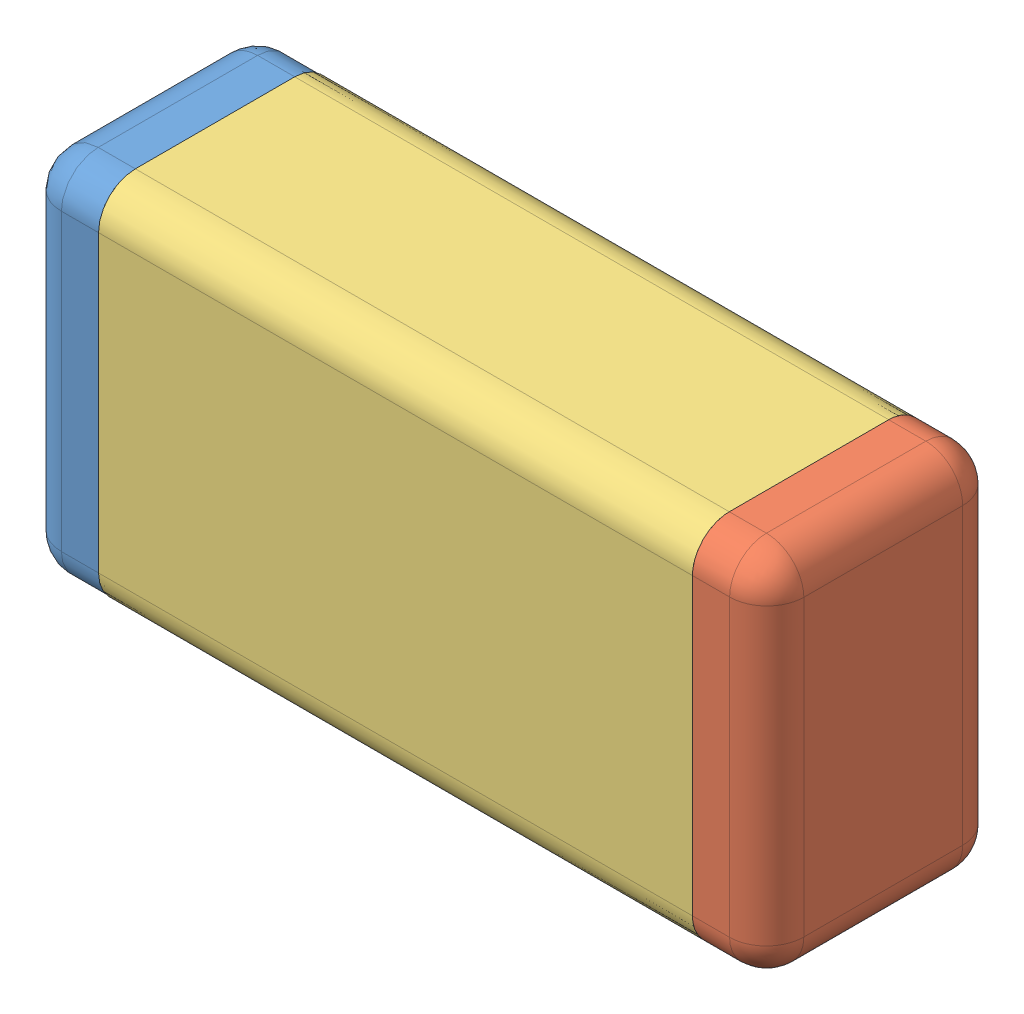
SolidWorks assembly C3_ASM, configuration Default. Lengths in mm.
Overall size (2.51 1.25 0.79).
4 component instances, 3 part files, 0 mates.
Components (placement in the parent):
- USER_LIBRARY-0805_2012M__CAP__1_ASM-1: USER_LIBRARY-0805_2012M__CAP__1_ASM [Default] at (16.2561 61.6965 -1.7324) x (1 0 0) z (0 1 0) size (2.51 0.79 1.25)
  - MANIFOLD_SOLID_BREP_12297-1: MANIFOLD_SOLID_BREP_12297 [Default] at origin size (0.25 0.79 1.25)
  - MANIFOLD_SOLID_BREP_13179-1: MANIFOLD_SOLID_BREP_13179 [Default] at origin size (0.25 0.79 1.25)
  - MANIFOLD_SOLID_BREP_13933-1: MANIFOLD_SOLID_BREP_13933 [Default] at origin size (2.01 0.79 1.24)
